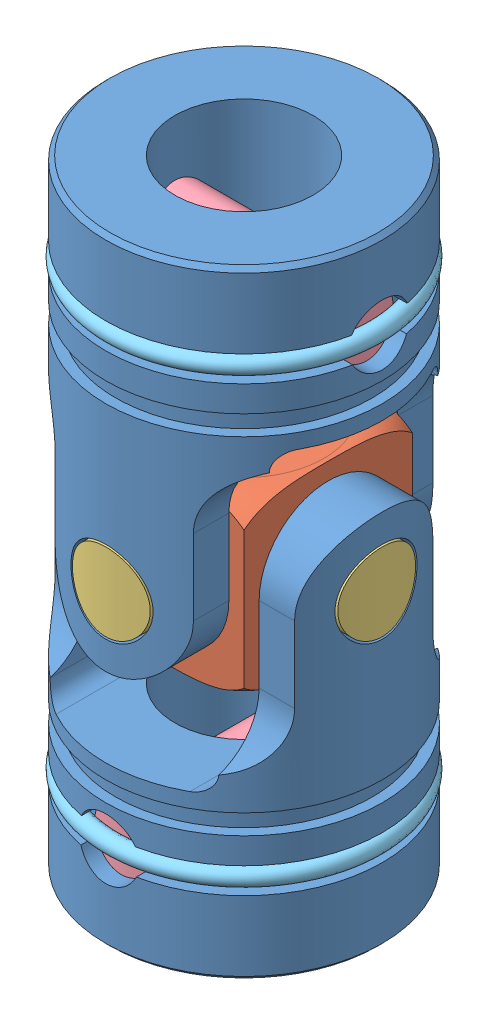
SolidWorks assembly 8mm U-Joint, configuration Straight. Lengths in mm.
Overall size (16.2 35.75 16.2).
9 component instances, 5 part files, 22 mates.
Components (placement in the parent):
- Part1^8mm U-Joint-1: Part1^8mm U-Joint [Default] at (0 -17.875 0) (virtual)
- Part1^8mm U-Joint-2: Part1^8mm U-Joint [Default] at (0 17.875 0) x (0 0 -1) z (-1 0 0) (virtual)
- Part2^8mm U-Joint-1: Part2^8mm U-Joint [Default] at origin (virtual)
- Part3^8mm U-Joint-1: Part3^8mm U-Joint [Default] at origin (virtual)
- Part3^8mm U-Joint-2: Part3^8mm U-Joint [Default] x (0 0 -1) z (1 0 0) (virtual)
- Part4^8mm U-Joint-1: Part4^8mm U-Joint [Default] at (0 -12.875 0) (virtual)
- Part4^8mm U-Joint-2: Part4^8mm U-Joint [Default] at (0 12.875 0) x (0 0 1) z (-1 0 0) (virtual)
- Part5^8mm U-Joint-1: Part5^8mm U-Joint [Default] at (0 -12.825 0) (virtual)
- Part5^8mm U-Joint-2: Part5^8mm U-Joint [Default] at (0 12.825 0) x (0 0 1) z (-1 0 0) (virtual)
Mates (geometry in assembly coordinates):
- Concentric1: concentric anti-aligned: cylinder of Part1^8mm U-Joint-1 through (-8 0 0) axis (1 0 0) radius 2.375; cylinder of Part2^8mm U-Joint-1 through (4.875 0 0) axis (-1 0 0) radius 2.25
- Concentric2: concentric anti-aligned: cylinder of Part1^8mm U-Joint-2 through (0 0 8) axis (0 0 -1) radius 2.375; cylinder of Part2^8mm U-Joint-1 through (0 0 -4.876) axis (0 0 1) radius 2.25
- Coincident1: coincident anti-aligned: plane of Part1^8mm U-Joint-2 through (8 -4 4.875) normal (0 0 -1); plane of Part2^8mm U-Joint-1 through (-4.875 5 4.875) normal (0 0 1)
- Coincident2: coincident anti-aligned: plane of Part1^8mm U-Joint-1 through (4.875 4 -8) normal (-1 0 0); plane of Part2^8mm U-Joint-1 through (4.875 5 4.875) normal (1 0 0)
- Concentric4: concentric aligned: cylinder of Part1^8mm U-Joint-2 through (0 0 8) axis (0 0 -1) radius 2.375; cylinder of Part3^8mm U-Joint-1 through (0 0 10) axis (0 0 -1) radius 2.25
- Concentric5: concentric anti-aligned: cylinder of Part1^8mm U-Joint-1 through (-8 0 0) axis (1 0 0) radius 2.375; cylinder of Part3^8mm U-Joint-2 through (10 0 0) axis (-1 0 0) radius 2.25
- Concentric6: concentric anti-aligned: cylinder of Part1^8mm U-Joint-1 through (0 4 0) axis (0 -1 0) radius 8; cylinder of Part3^8mm U-Joint-2 through (0 -2.25 0) axis (0 1 0) radius 8
- Concentric7: concentric aligned: cylinder of Part1^8mm U-Joint-2 through (0 -4 0) axis (0 1 0) radius 8; cylinder of Part3^8mm U-Joint-1 through (0 -2.25 0) axis (0 1 0) radius 8
- Coincident4: coincident: point of ?
- Parallel1: parallel anti-aligned: plane of Part1^8mm U-Joint-1 through (0 -17.875 0) normal (0 -1 0); plane of assembly through (0 0 0) normal (0 1 0)
- Coincident5: coincident aligned: plane of Part1^8mm U-Joint-1 through (0 -17.875 0) normal (0 0 1); plane of assembly through (0 0 0) normal (0 0 1)
- Straight: concentric anti-aligned: cylinder of Part1^8mm U-Joint-1 through (0 4 0) axis (0 -1 0) radius 8; cylinder of Part1^8mm U-Joint-2 through (0 -4 0) axis (0 1 0) radius 8
- Concentric8: concentric anti-aligned: cylinder of Part1^8mm U-Joint-1 through (0 -12.875 -8) axis (0 0 1) radius 1.75; cylinder of Part4^8mm U-Joint-1 through (0 -12.875 8) axis (0 0 -1) radius 1.75
- Concentric9: concentric aligned: cylinder of Part1^8mm U-Joint-1 through (0 -17.875 0) axis (0 1 0) radius 7.1; cylinder of Part4^8mm U-Joint-1 through (0 -14.625 0) axis (0 1 0) radius 7.1
- Concentric10: concentric anti-aligned: cylinder of Part1^8mm U-Joint-2 through (8 12.875 0) axis (-1 0 0) radius 1.75; cylinder of Part4^8mm U-Joint-2 through (-8 12.875 0) axis (1 0 0) radius 1.75
- Concentric11: concentric anti-aligned: cylinder of Part1^8mm U-Joint-2 through (0 17.875 0) axis (0 -1 0) radius 7.1; cylinder of Part4^8mm U-Joint-2 through (0 11.125 0) axis (0 1 0) radius 7.1
- Concentric12: concentric aligned: cylinder of Part1^8mm U-Joint-1 through (0 4 0) axis (0 -1 0) radius 8; line of Part5^8mm U-Joint-1 through (1.1 0 -12.275) axis (0 0 -1)
- Concentric13: concentric anti-aligned: cylinder of Part1^8mm U-Joint-2 through (0 -4 0) axis (0 1 0) radius 8; line of Part5^8mm U-Joint-2 through (0 13.375 0) axis (0 -1 0)
- Symmetric1: symmetric aligned: plane of Part1^8mm U-Joint-1 through (8 -13.575 0) normal (0 1 0); plane of Part1^8mm U-Joint-1 through (8 -12.075 0) normal (0 -1 0); plane of Part5^8mm U-Joint-1 through (0 -12.825 0) normal (0 1 0)
- Symmetric2: symmetric aligned: plane of Part1^8mm U-Joint-2 through (0 13.575 -8) normal (0 -1 0); plane of Part1^8mm U-Joint-2 through (0 12.075 -8) normal (0 1 0); plane of Part5^8mm U-Joint-2 through (0 12.825 0) normal (0 1 0)
- Coincident6: coincident aligned: plane of Part1^8mm U-Joint-1 through (0 -17.875 0) normal (0 0 1); plane of Part5^8mm U-Joint-1 through (0 -12.825 0) normal (0 0 1)
- Coincident7: coincident aligned: plane of Part1^8mm U-Joint-2 through (0 17.875 0) normal (-1 0 0); plane of Part5^8mm U-Joint-2 through (0 12.825 0) normal (-1 0 0)
